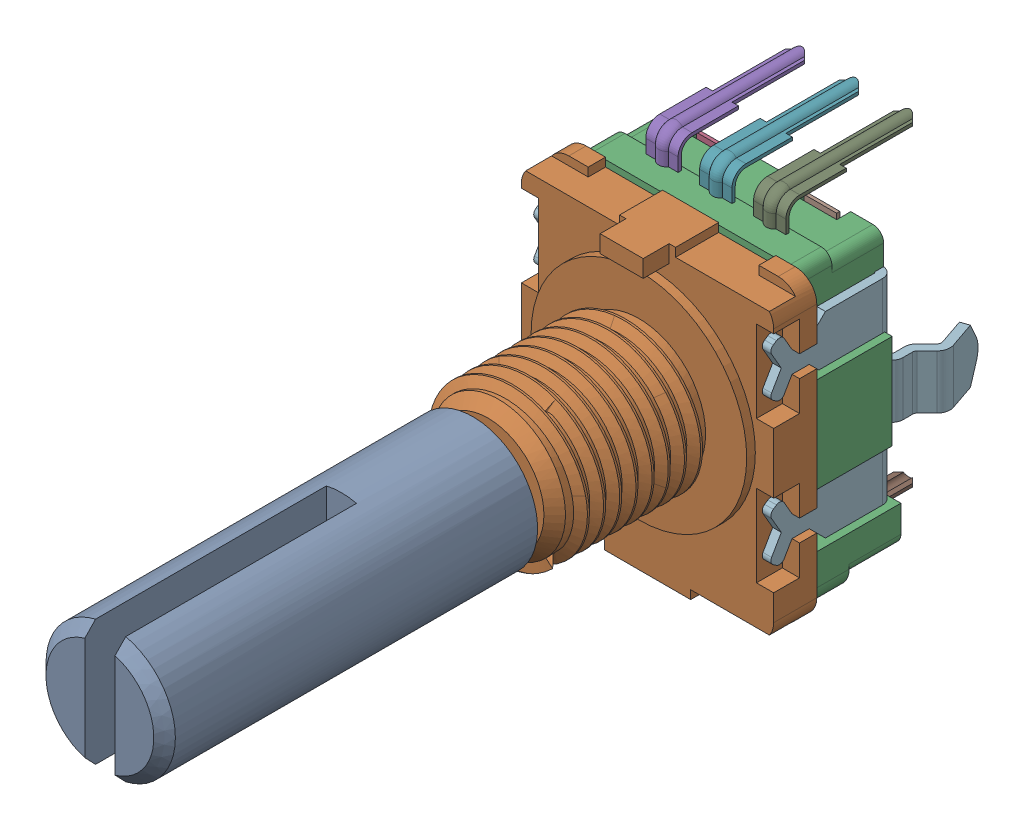
SolidWorks assembly Body_1, configuration Défaut. Lengths in mm.
Overall size (13.1 15.13 35.07).
16 component instances, 7 part files, 0 mates.
Components (placement in the parent):
- Imported-1: Imported [Défaut] at (0 0 13.6) size (6 6 18)
- Imported_2-1: Imported_2 [Défaut] at (0 0 3.443) size (11.7 13.8 9.4)
- Imported_3-1: Imported_3 [Défaut] at (-0.85 -0.6436 6.5892) size (11.7 13.3 3.9)
- Imported-2: Imported [Défaut] at (0 0 6.6326) size (13.1 14.95 9.45)
  - Imported_2-1: Imported_2 [Défaut] at (-2.5 7.575 -10.2243) x (0 -1 0) z (0 0 1) size (2.34 1.5 6.65)
    - SOLID-1: SOLID [Défaut] at origin size (0.6 1.5 0.15)
    - SOLID_2-1: SOLID_2 [Défaut] at origin size (2.15 1.5 6.65)
  - Imported_2-2: Imported_2 [Défaut] at (0 7.575 -10.2243) x (0 -1 0) z (0 0 1) size (2.34 1.5 6.65)
    - SOLID-1: SOLID [Défaut] at origin size (0.6 1.5 0.15)
    - SOLID_2-1: SOLID_2 [Défaut] at origin size (2.15 1.5 6.65)
  - Imported_2-3: Imported_2 [Défaut] at (2.5 7.575 -10.2243) x (0 -1 0) z (0 0 1) size (2.34 1.5 6.65)
    - SOLID-1: SOLID [Défaut] at origin size (0.6 1.5 0.15)
    - SOLID_2-1: SOLID_2 [Défaut] at origin size (2.15 1.5 6.65)
  - Imported_4-1: Imported_4 [Défaut] at (-2.5 -7.075 -10.2243) x (0 1 0) z (0 0 1) size (2.15 1.5 4.73)
  - Imported_4-2: Imported_4 [Défaut] at (2.5 -7.075 -10.2243) x (0 1 0) z (0 0 1) size (2.15 1.5 4.73)
  - Imported_5-1: Imported_5 [Défaut] at (-24.7094 3.8245 8.4125) size (13.1 9.9 9.18)
